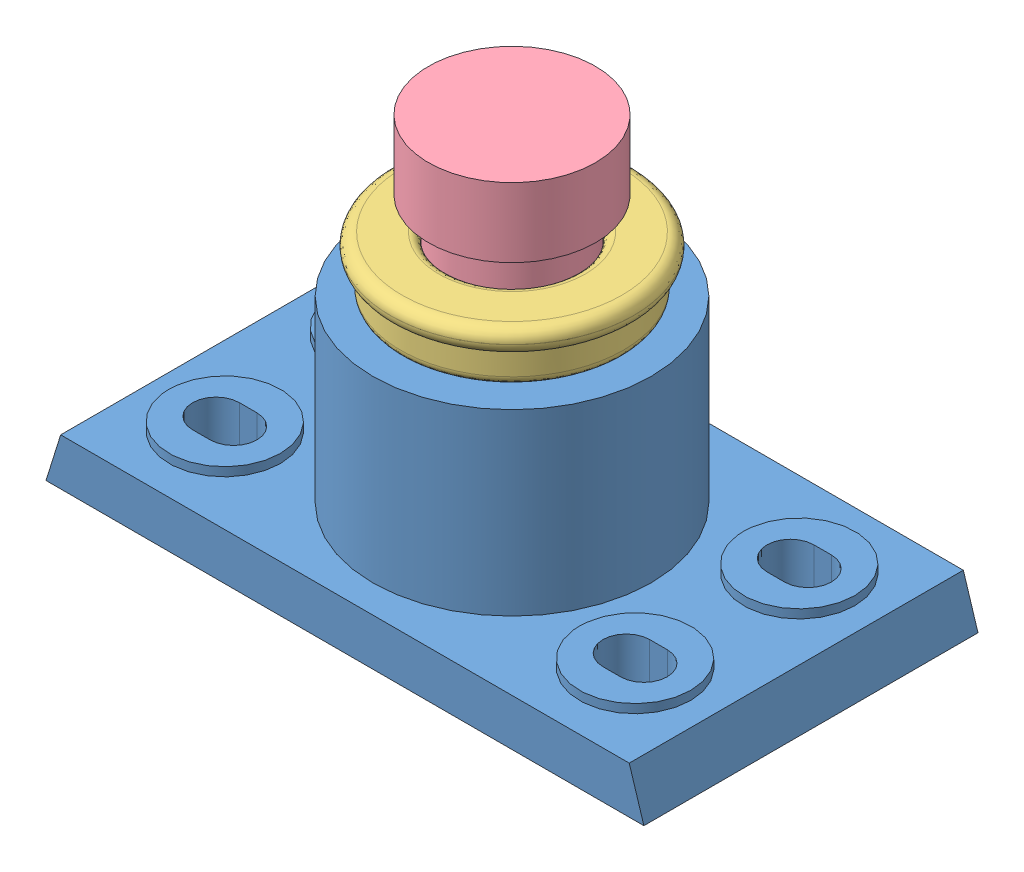
SolidWorks assembly Assem1, configuration Default. Lengths in mm.
Overall size (204 130.66 114).
4 component instances, 4 part files, 8 mates.
Components (placement in the parent):
- body-1: body [Default] at (81.0045 68.7174 96.5089) size (204 77 114)
- pad-1: pad [Default] at (81.0045 84.7174 153.5089) x (-1 0 0) z (0 1 0) size (44.17 44.17 16.17)
- bush-1: bush [Default] at (81.0045 102.0906 153.5089) x (0 0 -1) z (1 0 0) size (83 77 83)
- shaft-1: shaft [Default] at (81.0045 100.7174 153.5089) x (0.422658 0 0.906289) z (-0.906289 0 0.422658) size (57 98.66 57)
Mates (geometry in assembly coordinates):
- Coincident1: coincident anti-aligned: plane of body-1 through (81.0045 84.7174 153.5089) normal (0 1 0); plane of pad-1 through (81.0045 84.7174 153.5089) normal (0 -1 0)
- Concentric1: concentric aligned: circle of pad-1; circle of shaft-1
- Coincident3: coincident anti-aligned: cylinder of body-1 through (81.0045 84.7174 153.5089) axis (0 1 0) radius 31; circle of bush-1
- Coincident6: coincident: point of pad-1; plane of shaft-1 through (81.0045 100.7174 153.5089) normal (0 -1 0)
- Concentric3: concentric anti-aligned: circle of shaft-1; cylinder of body-1 through (81.0045 97.7174 153.5089) axis (0 1 0) radius 32.5
- Coincident7: coincident aligned: circle of body-1; circle of pad-1
- Coincident8: coincident anti-aligned: circle of body-1; cylinder of bush-1 through (59.0045 89.7174 153.5089) axis (0 -1 0) radius 1.5
- Coincident9: coincident anti-aligned: plane of body-1 through (81.0045 145.7174 210.5089) normal (0 1 0); plane of bush-1 through (81.0045 145.7174 122.5089) normal (0 -1 0)
